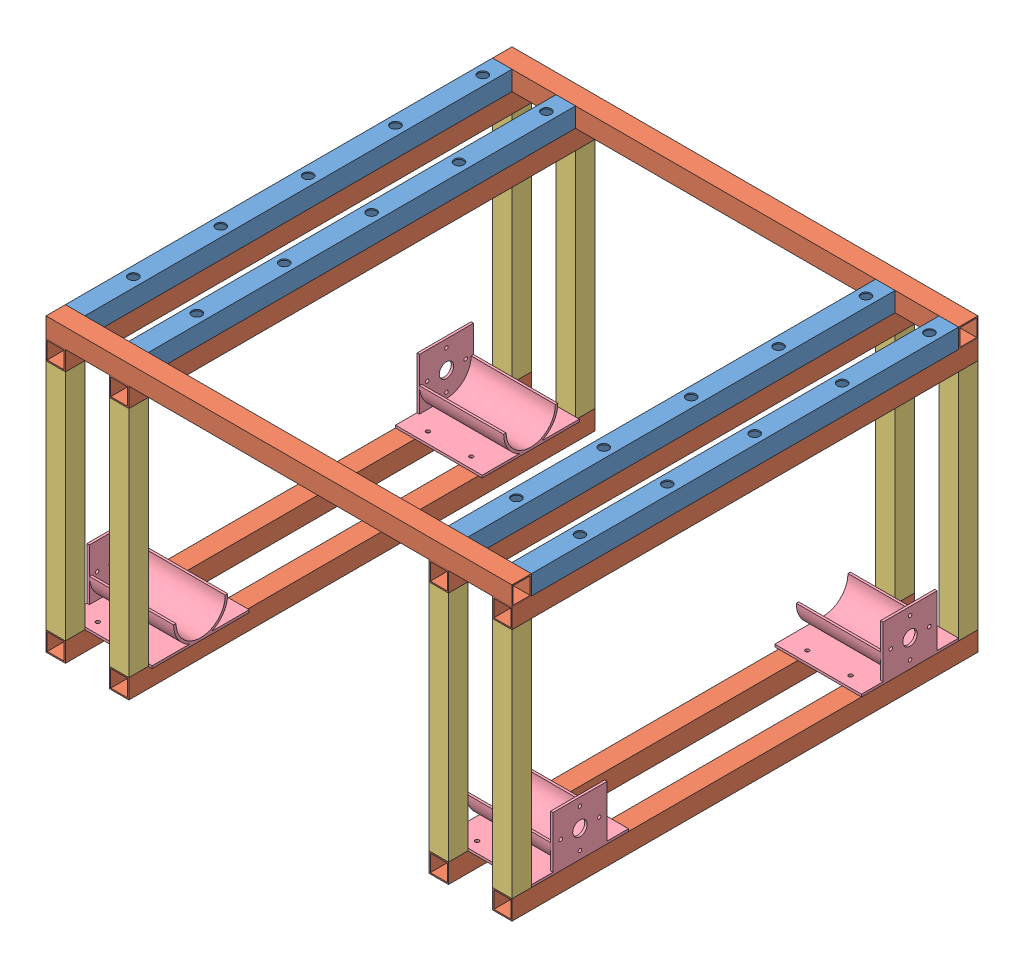
SolidWorks assembly frame4shell, configuration Default. Lengths in mm.
Overall size (609.6 381 609.6).
31 component instances, 4 part files, 26 mates.
Components (placement in the parent):
- topPlate-1: topPlate [Default] at origin size (609.6 25.4 609.6)
  - 22_stube-1: 22_stube [Default] at (12.7 0 571.5) x (1 0 0) z (0 1 0) size (25.4 558.8 25.4)
  - 22_stube-2: 22_stube [Default] at (95.758 0 571.5) x (1 0 0) z (0 1 0) size (25.4 558.8 25.4)
  - 22_stube-3: 22_stube [Default] at (596.9 0 571.5) x (1 0 0) z (0 1 0) size (25.4 558.8 25.4)
  - 22_stube-4: 22_stube [Default] at (513.842 0 571.5) x (1 0 0) z (0 1 0) size (25.4 558.8 25.4)
  - 24_stube-1: 24_stube [Default] x (0 -1 0) z (0 0 1) size (25.4 609.6 25.4)
  - 24_stube-2: 24_stube [Default] at (609.6 0 584.2) x (0 1 0) z (0 0 1) size (25.4 609.6 25.4)
- hangDownDrilled-1: hangDownDrilled [Default] at (12.7 -342.9 584.2) size (25.4 355.6 609.6)
  - 12_stube-1: 12_stube [Default] at origin size (25.4 304.8 25.4)
  - 24_stube-1: 24_stube [Default] at (0 -12.7 12.7) x (1 0 0) z (0 1 0) size (25.4 609.6 25.4)
  - 24_stube-2: 24_stube [Default] at (0 317.5 -596.9) x (0 -1 0) z (-1 0 0) size (25.4 609.6 25.4)
  - 12_stube-2: 12_stube [Default] at (0 304.8 -584.2) x (-1 0 0) z (0 0 1) size (25.4 304.8 25.4)
- hangDownDrilled-2: hangDownDrilled [Default] at (95.758 -342.9 584.2) size (25.4 355.6 609.6)
  - 12_stube-1: 12_stube [Default] at origin size (25.4 304.8 25.4)
  - 24_stube-1: 24_stube [Default] at (0 -12.7 12.7) x (1 0 0) z (0 1 0) size (25.4 609.6 25.4)
  - 24_stube-2: 24_stube [Default] at (0 317.5 -596.9) x (0 -1 0) z (-1 0 0) size (25.4 609.6 25.4)
  - 12_stube-2: 12_stube [Default] at (0 304.8 -584.2) x (-1 0 0) z (0 0 1) size (25.4 304.8 25.4)
- hangDownDrilled-3: hangDownDrilled [Default] at (513.842 -342.9 584.2) size (25.4 355.6 609.6)
  - 12_stube-1: 12_stube [Default] at origin size (25.4 304.8 25.4)
  - 24_stube-1: 24_stube [Default] at (0 -12.7 12.7) x (1 0 0) z (0 1 0) size (25.4 609.6 25.4)
  - 24_stube-2: 24_stube [Default] at (0 317.5 -596.9) x (0 -1 0) z (-1 0 0) size (25.4 609.6 25.4)
  - 12_stube-2: 12_stube [Default] at (0 304.8 -584.2) x (-1 0 0) z (0 0 1) size (25.4 304.8 25.4)
- hangDownDrilled-4: hangDownDrilled [Default] at (596.9 -342.9 584.2) size (25.4 355.6 609.6)
  - 12_stube-1: 12_stube [Default] at origin size (25.4 304.8 25.4)
  - 24_stube-1: 24_stube [Default] at (0 -12.7 12.7) x (1 0 0) z (0 1 0) size (25.4 609.6 25.4)
  - 24_stube-2: 24_stube [Default] at (0 317.5 -596.9) x (0 -1 0) z (-1 0 0) size (25.4 609.6 25.4)
  - 12_stube-2: 12_stube [Default] at (0 304.8 -584.2) x (-1 0 0) z (0 0 1) size (25.4 304.8 25.4)
- motor mount-1: motor mount [Default] at (496.189 -307.5178 508) x (0 0 -1) z (1 0 0) size (127 70.87 113.41)
- motor mount-2: motor mount [Default] at (113.411 -307.5178 508) x (0 0 1) z (-1 0 0) size (127 70.87 113.41)
- motor mount-3: motor mount [Default] at (496.189 -307.5178 76.2) x (0 0 -1) z (1 0 0) size (127 70.87 113.41)
- motor mount-4: motor mount [Default] at (113.411 -307.5178 76.2) x (0 0 1) z (-1 0 0) size (127 70.87 113.41)
Mates (geometry in assembly coordinates):
- Coincident1: coincident: point of topPlate-1; point of assembly
- Coincident2: coincident aligned: plane of topPlate-1/22_stube-3 through (609.6 12.7 12.7) normal (1 0 0); plane of hangDownDrilled-4/24_stube-2 through (609.6 -12.7 596.9) normal (1 0 0)
- Coincident3: coincident anti-aligned: plane of topPlate-1/22_stube-3 through (584.2 -12.7 12.7) normal (0 -1 0); plane of hangDownDrilled-4/24_stube-2 through (584.2 -12.7 596.9) normal (0 1 0)
- Coincident4: coincident aligned: plane of topPlate-1/24_stube-2 through (0 -12.7 596.9) normal (0 0 1); plane of hangDownDrilled-4/12_stube-1 through (584.2 -38.1 596.9) normal (0 0 1)
- Coincident5: coincident aligned: plane of topPlate-1/24_stube-2 through (0 -12.7 596.9) normal (0 0 1); plane of hangDownDrilled-3/12_stube-1 through (501.142 -38.1 596.9) normal (0 0 1)
- Coincident6: coincident aligned: plane of topPlate-1/22_stube-4 through (501.142 12.7 12.7) normal (-1 0 0); plane of hangDownDrilled-3/24_stube-2 through (501.142 -12.7 596.9) normal (-1 0 0)
- Coincident7: coincident anti-aligned: plane of topPlate-1/22_stube-4 through (501.142 -12.7 12.7) normal (0 -1 0); plane of hangDownDrilled-3/24_stube-2 through (501.142 -12.7 596.9) normal (0 1 0)
- Coincident8: coincident anti-aligned: plane of topPlate-1/22_stube-2 through (83.058 -12.7 12.7) normal (0 -1 0); plane of hangDownDrilled-2/24_stube-2 through (83.058 -12.7 596.9) normal (0 1 0)
- Coincident9: coincident anti-aligned: plane of topPlate-1/22_stube-1 through (0 -12.7 12.7) normal (0 -1 0); plane of hangDownDrilled-1/24_stube-2 through (0 -12.7 596.9) normal (0 1 0)
- Coincident10: coincident aligned: plane of topPlate-1/24_stube-2 through (0 -12.7 596.9) normal (0 0 1); plane of hangDownDrilled-1/12_stube-1 through (0 -38.1 596.9) normal (0 0 1)
- Coincident11: coincident aligned: plane of topPlate-1/24_stube-2 through (0 -12.7 596.9) normal (0 0 1); plane of hangDownDrilled-2/12_stube-1 through (83.058 -38.1 596.9) normal (0 0 1)
- Coincident12: coincident anti-aligned: plane of topPlate-1/22_stube-1 through (0 -12.7 12.7) normal (0 -1 0); plane of hangDownDrilled-1/24_stube-2 through (0 -12.7 596.9) normal (0 1 0)
- Coincident13: coincident aligned: plane of topPlate-1/22_stube-1 through (0 12.7 12.7) normal (-1 0 0); plane of hangDownDrilled-1/24_stube-2 through (0 -12.7 596.9) normal (-1 0 0)
- Coincident14: coincident aligned: plane of topPlate-1/22_stube-2 through (108.458 12.7 12.7) normal (1 0 0); plane of hangDownDrilled-2/24_stube-2 through (108.458 -12.7 596.9) normal (1 0 0)
- Coincident24: coincident aligned: plane of hangDownDrilled-4/24_stube-1 through (609.6 -342.9 -12.7) normal (1 0 0); plane of motor mount-1 through (609.6 -307.5178 508) normal (1 0 0)
- Coincident25: coincident aligned: plane of hangDownDrilled-4/24_stube-1 through (609.6 -342.9 -12.7) normal (1 0 0); plane of motor mount-3 through (609.6 -307.5178 76.2) normal (1 0 0)
- Coincident26: coincident aligned: plane of hangDownDrilled-1/24_stube-1 through (0 -342.9 -12.7) normal (-1 0 0); plane of motor mount-2 through (0 -307.5178 508) normal (-1 0 0)
- Coincident28: coincident aligned: plane of hangDownDrilled-1/24_stube-1 through (0 -342.9 -12.7) normal (-1 0 0); plane of motor mount-4 through (0 -307.5178 76.2) normal (-1 0 0)
- Coincident29: coincident anti-aligned: plane of hangDownDrilled-1/24_stube-1 through (0 -342.9 -12.7) normal (0 1 0); plane of motor mount-4 through (3.175 -342.9 76.2) normal (0 -1 0)
- Coincident30: coincident anti-aligned: plane of hangDownDrilled-1/24_stube-1 through (0 -342.9 -12.7) normal (0 1 0); plane of motor mount-2 through (3.175 -342.9 508) normal (0 -1 0)
- Coincident31: coincident anti-aligned: plane of hangDownDrilled-3/24_stube-1 through (501.142 -342.9 -12.7) normal (0 1 0); plane of motor mount-1 through (606.425 -342.9 508) normal (0 -1 0)
- Coincident32: coincident anti-aligned: plane of hangDownDrilled-3/24_stube-1 through (501.142 -342.9 -12.7) normal (0 1 0); plane of motor mount-3 through (606.425 -342.9 76.2) normal (0 -1 0)
- Coincident33: coincident anti-aligned: plane of hangDownDrilled-1/12_stube-2 through (25.4 -342.9 12.7) normal (0 0 1); plane of motor mount-4 through (3.175 -307.5178 12.7) normal (0 0 -1)
- Coincident34: coincident anti-aligned: plane of hangDownDrilled-1/12_stube-1 through (0 -38.1 571.5) normal (0 0 -1); plane of motor mount-2 through (3.175 -307.5178 571.5) normal (0 0 1)
- Coincident35: coincident anti-aligned: plane of hangDownDrilled-3/12_stube-2 through (526.542 -342.9 12.7) normal (0 0 1); plane of motor mount-3 through (606.425 -307.5178 12.7) normal (0 0 -1)
- Coincident36: coincident anti-aligned: plane of hangDownDrilled-3/12_stube-1 through (501.142 -38.1 571.5) normal (0 0 -1); plane of motor mount-1 through (606.425 -307.5178 571.5) normal (0 0 1)
